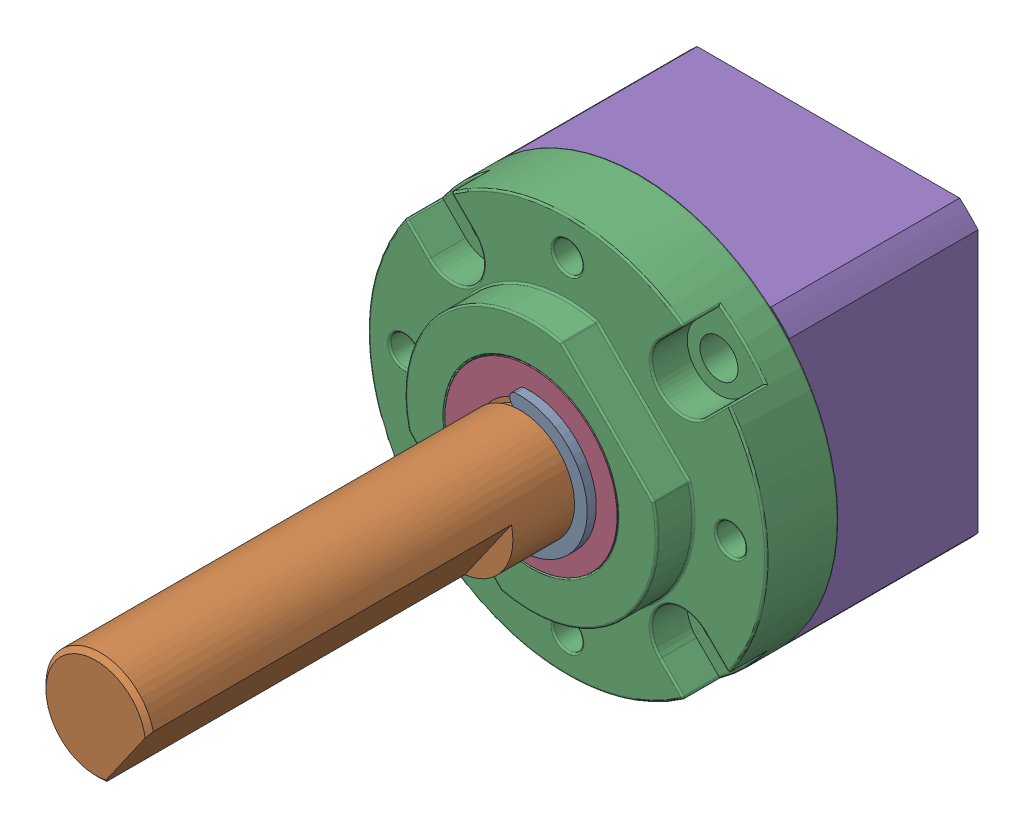
SolidWorks assembly Ring Gear.stp, configuration Default. Lengths in mm.
Overall size (21.95 21.95 40.4).
7 component instances, 5 part files, 0 mates.
Components (placement in the parent):
- Front Plate.stp-1: Front Plate.stp [Default] at (0.0152 10.101 56.6116) x (0 1 0) z (1 0 0) size (21.95 30.5 21.95)
  - Shaft.stp-1: Shaft.stp [Default] x (-0.819152 0 -0.573576) z (0.573576 0 -0.819152) size (7.4 30.3 6.7)
    - Retaining Ring.stp-1: Retaining Ring.stp [Default] at (0 16.65 0) x (-1 0 0) z (0 -1 0) size (7.4 6.16 0.5)
    - Shaft-0.stp-1: Shaft-0.stp [Default] at origin size (6 30.3 6)
  - Front Plate-1.stp-1: Front Plate-1.stp [Default] at origin size (21.95 6.5 21.95)
  - Front Plate-2.stp-1: Front Plate-2.stp [Default] at origin size (9.5 6 9.5)
- Ring Gear Body.stp-1: Ring Gear Body.stp [Default] at (0.0152 10.101 56.6116) x (0 1 0) z (1 0 0) size (16.5 10.4 16.5)
